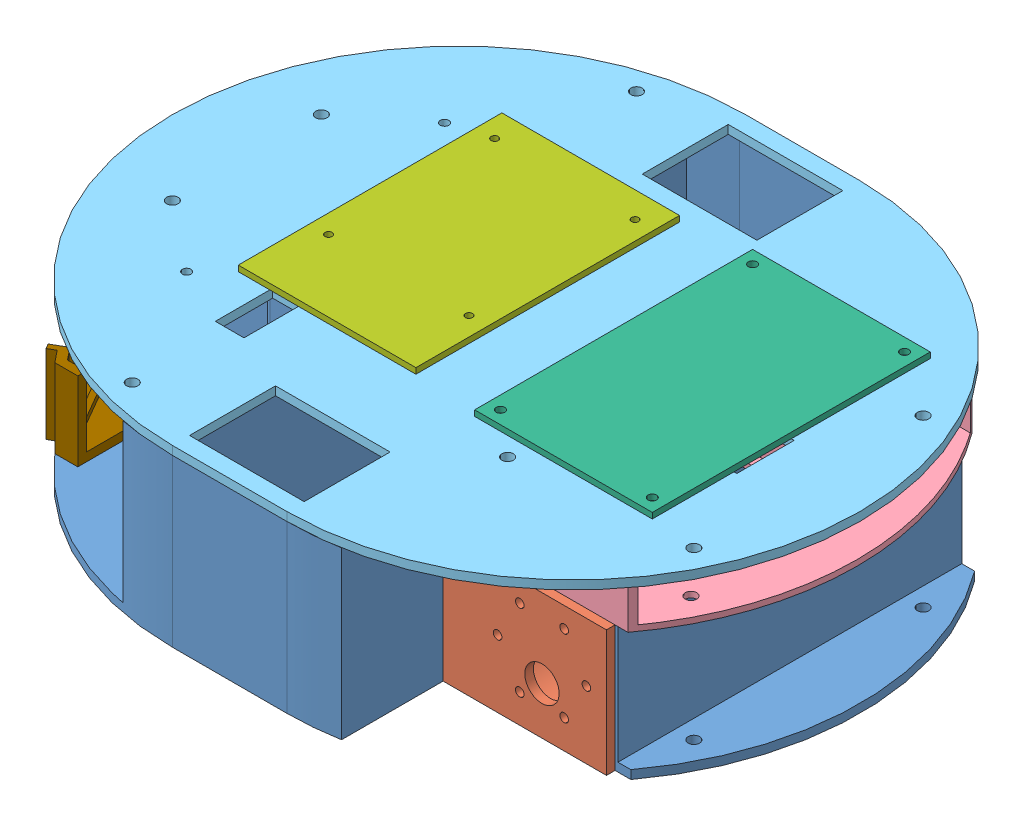
SolidWorks assembly 小车组装, configuration 默认. Lengths in mm.
Overall size (242 82 200).
9 component instances, 9 part files, 22 mates.
Components (placement in the parent):
- 小车底盘Pro-1: 小车底盘Pro [默认] at (-61.6429 -15.0083 5) x (0 0 -1) z (1 0 0) size (200 67 240)
- 电机安装架-1: 电机安装架 [默认] at (-9.6429 8.4917 65) size (57 44 24)
- 电机锁架-1: 电机锁架 [默认] at (-30.1429 28.9917 44) x (0 0 -1) z (-1 0 0) size (25 20.5 41)
- 电机压板-1: 电机压板 [默认] at (-62.6429 28.9917 5) x (0 0 -1) z (1 0 0) size (120 14 84.5)
- 控制器安装盘-1: 控制器安装盘 [默认] at (-61.6429 42.9917 5) x (0 0 -1) z (1 0 0) size (200 8 240)
- 控制板托架STM32-1: 控制板托架STM32 [默认] at (-16.6429 57.9917 5) x (0 0 1) z (1 0 0) size (97 12 62)
- 控制板托架树莓派-2: 控制板托架树莓派 [默认] at (-101.6429 57.9917 5) x (0 0 -1) z (-1 0 0) size (92 12 62)
- 超声波传感器安装板-1: 超声波传感器安装板 [默认] at (-201.6429 15.4917 5) x (0 0 -1) z (0 -1 0) size (22 5 49)
- 车头前盖-1: 车头前盖 [默认] at (-101.6429 -9.0083 5) x (0 0 -1) z (1 0 0) size (130 27.5 34)
Mates (geometry in assembly coordinates):
- 重合2: coincident anti-aligned: line of 电机安装架-1 through (10.8571 -12.0083 65) axis (-1 0 0); line of 小车底盘Pro-1 through (-30.1429 -12.0083 65) axis (1 0 0)
- 重合3: coincident anti-aligned: line of 电机安装架-1 through (10.8571 28.9917 44) axis (0 0 1); line of 小车底盘Pro-1 through (10.8571 28.9917 65) axis (0 0 -1)
- 重合4: coincident anti-aligned: line of 电机安装架-1 through (-30.1429 28.9917 44) axis (1 0 0); line of 电机锁架-1 through (10.8571 28.9917 44) axis (-1 0 0)
- 重合5: coincident anti-aligned: plane of 小车底盘Pro-1 through (10.8571 28.9917 5) normal (-1 0 0); plane of 电机锁架-1 through (10.8571 26.9917 44) normal (1 0 0)
- 重合6: coincident aligned: line of 电机安装架-1 through (10.8571 28.9917 44) axis (0 0 1); line of 电机锁架-1 through (10.8571 28.9917 19) axis (0 0 1)
- 重合11: coincident anti-aligned: plane of 电机安装架-1 through (-44.1429 28.9917 68) normal (0 1 0); plane of 电机压板-1 through (-62.6429 28.9917 5) normal (0 -1 0)
- 重合12: coincident aligned: plane of 小车底盘Pro-1 through (-61.6429 -15.0083 -55) normal (0 0 -1); plane of 电机压板-1 through (-62.6429 30.9917 -55) normal (0 0 -1)
- 重合14: coincident aligned: line of 小车底盘Pro-1 through (-33.1429 42.9917 65) axis (0 -1 0); line of 电机压板-1 through (-33.1429 42.9917 65) axis (0 -1 0)
- 重合15: coincident anti-aligned: plane of 电机压板-1 through (-62.6429 42.9917 5) normal (0 1 0); plane of 控制器安装盘-1 through (-61.6429 42.9917 5) normal (0 -1 0)
- 重合17: coincident anti-aligned: line of 小车底盘Pro-1 through (-101.6429 42.9917 105) axis (1 0 0); line of 控制器安装盘-1 through (-61.6429 42.9917 105) axis (-1 0 0)
- 重合18: coincident aligned: line of 小车底盘Pro-1 through (-61.6429 42.9917 -95) axis (0 -1 0); line of 控制器安装盘-1 through (-61.6429 45.9917 -95) axis (0 -1 0)
- 重合29: coincident anti-aligned: line of 控制板托架STM32-1 through (-32.6429 45.9917 38) axis (0 1 0); line of 控制器安装盘-1 through (-32.6429 50.9917 38) axis (0 -1 0)
- 重合30: coincident anti-aligned: line of 控制器安装盘-1 through (-30.6429 50.9917 32) axis (0 -1 0); line of 控制板托架STM32-1 through (-30.6429 45.9917 32) axis (0 1 0)
- 重合31: coincident anti-aligned: line of 控制器安装盘-1 through (-32.6429 45.9917 38) axis (0 0 -1); line of 控制板托架STM32-1 through (-32.6429 45.9917 32) axis (0 0 1)
- 重合32: coincident anti-aligned: line of 控制器安装盘-1 through (-115.6429 50.9917 38) axis (0 -1 0); line of 控制板托架树莓派-2 through (-115.6429 45.9917 38) axis (0 1 0)
- 重合33: coincident anti-aligned: line of 控制器安装盘-1 through (-117.6429 50.9917 32) axis (0 -1 0); line of 控制板托架树莓派-2 through (-117.6429 45.9917 32) axis (0 1 0)
- 重合34: coincident anti-aligned: line of 控制器安装盘-1 through (-115.6429 45.9917 38) axis (0 0 -1); line of 控制板托架树莓派-2 through (-115.6429 45.9917 32) axis (0 0 1)
- 重合38: coincident aligned: line of 超声波传感器安装板-1 through (-187.6429 -29.0083 16) axis (0 0 -1); line of 车头前盖-1 through (-187.6429 -29.0083 16) axis (0 0 -1)
- 重合39: coincident anti-aligned: line of 超声波传感器安装板-1 through (-187.6429 -24.0083 16) axis (0 -1 0); line of 车头前盖-1 through (-187.6429 -29.0083 16) axis (0 1 0)
- 重合41: coincident anti-aligned: line of 小车底盘Pro-1 through (-184.6429 -12.0083 24) axis (0 0 -1); line of 车头前盖-1 through (-184.6429 -12.0083 -14) axis (0 0 1)
- 重合43: coincident: plane of 小车底盘Pro-1 through (-61.6429 42.9917 24) normal (0 0 1); line of 车头前盖-1 through (-169.6429 -12.0083 24) axis (0 1 0)
- 重合44: coincident: plane of 小车底盘Pro-1 through (-61.6429 -12.0083 5) normal (0 1 0); line of 车头前盖-1 through (-169.6429 -12.0083 70) axis (0 0 -1)
